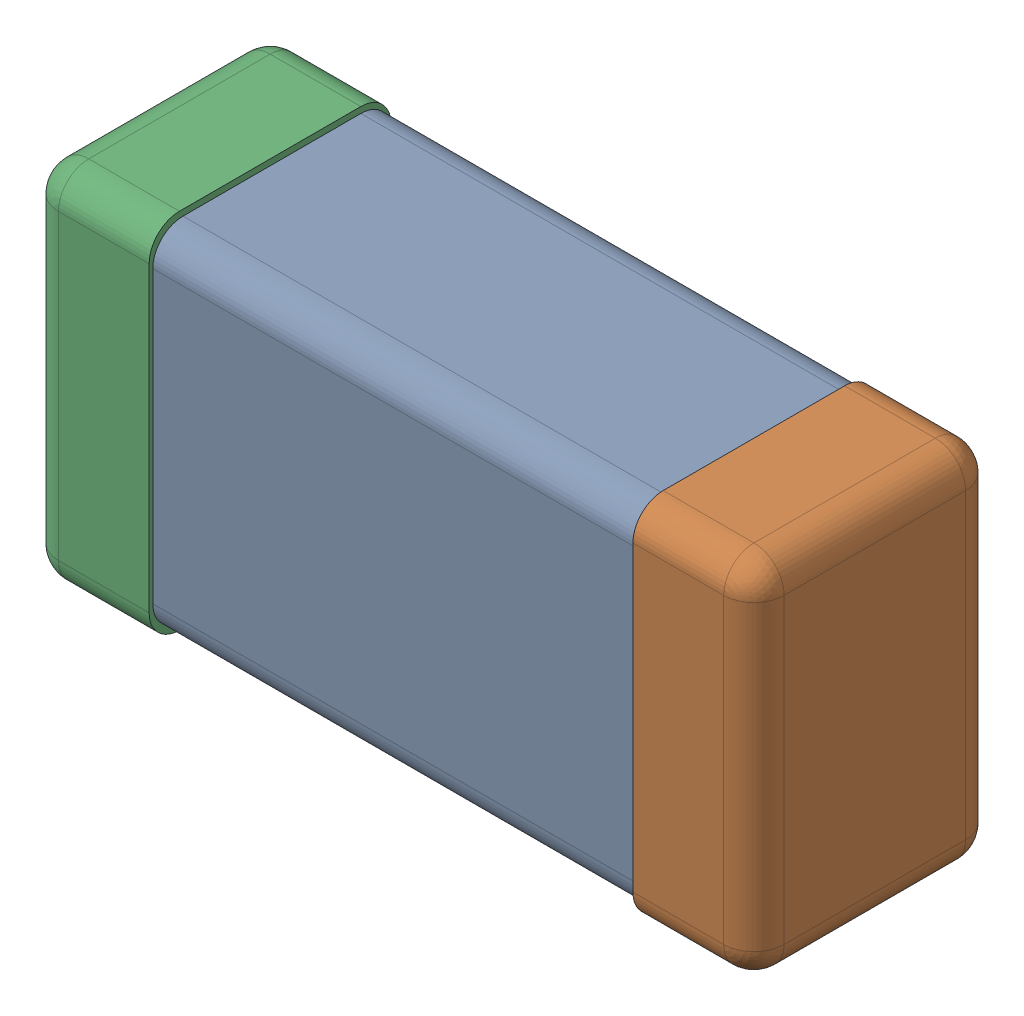
SolidWorks assembly C0201_020_9, configuration Standard. Lengths in mm.
Overall size (0.6 0.3 0.2).
3 component instances, 3 part files, 0 mates.
Components (placement in the parent):
- Part 3_2-1: Part 3_2 [Standard] at (0 0 -7.3015) size (0.5 0.29 0.2)
- Part 2_2-1: Part 2_2 [Standard] at (0 0 -7.3) size (0.1 0.3 0.2)
- Part 1_2-1: Part 1_2 [Standard] at (0 0 -7.3) size (0.1 0.3 0.2)
